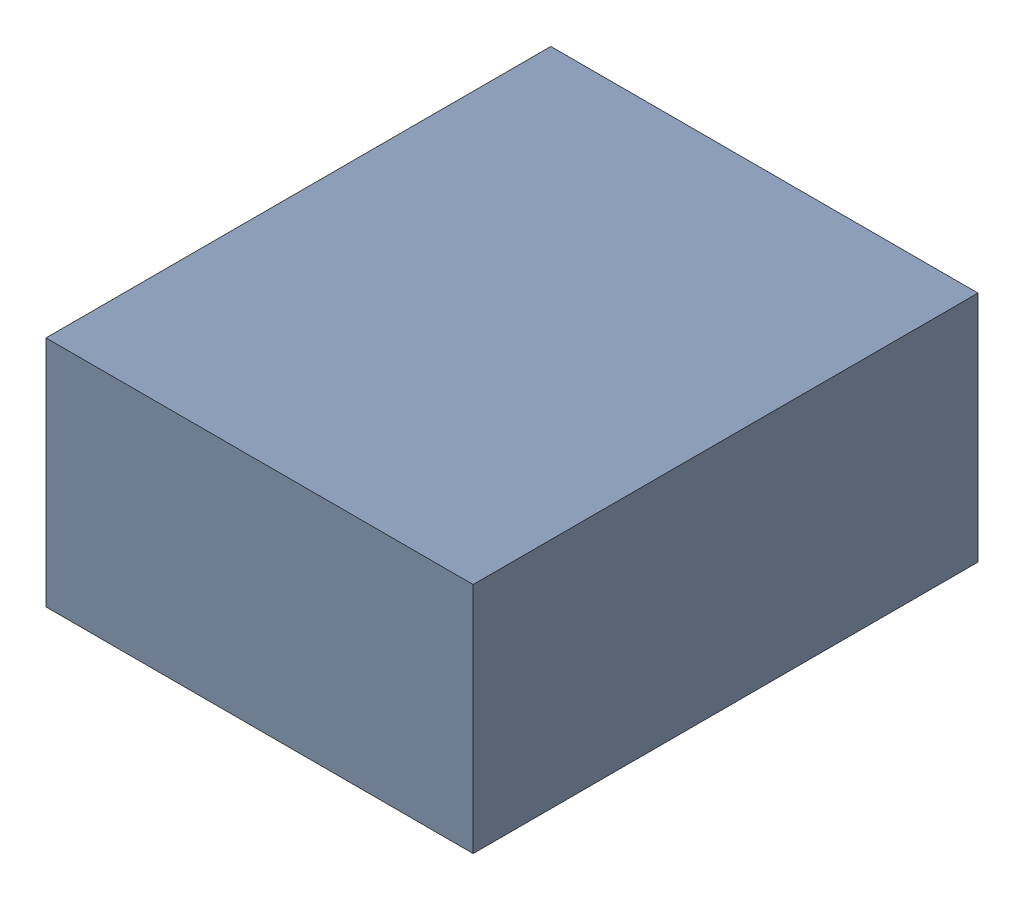
SolidWorks assembly C28_TDA4, configuration Standard. Lengths in mm.
Overall size (1.1 0.6 1.3).
2 component instances, 1 part files, 0 mates.
Components (placement in the parent):
- 885542240-1: 885542240 [Standard] at (0.38 -57.19 0) size (1.1 0.6 1.3)
  - Extruded_28-1: Extruded_28 [Standard] at origin size (1.1 0.6 1.3)
